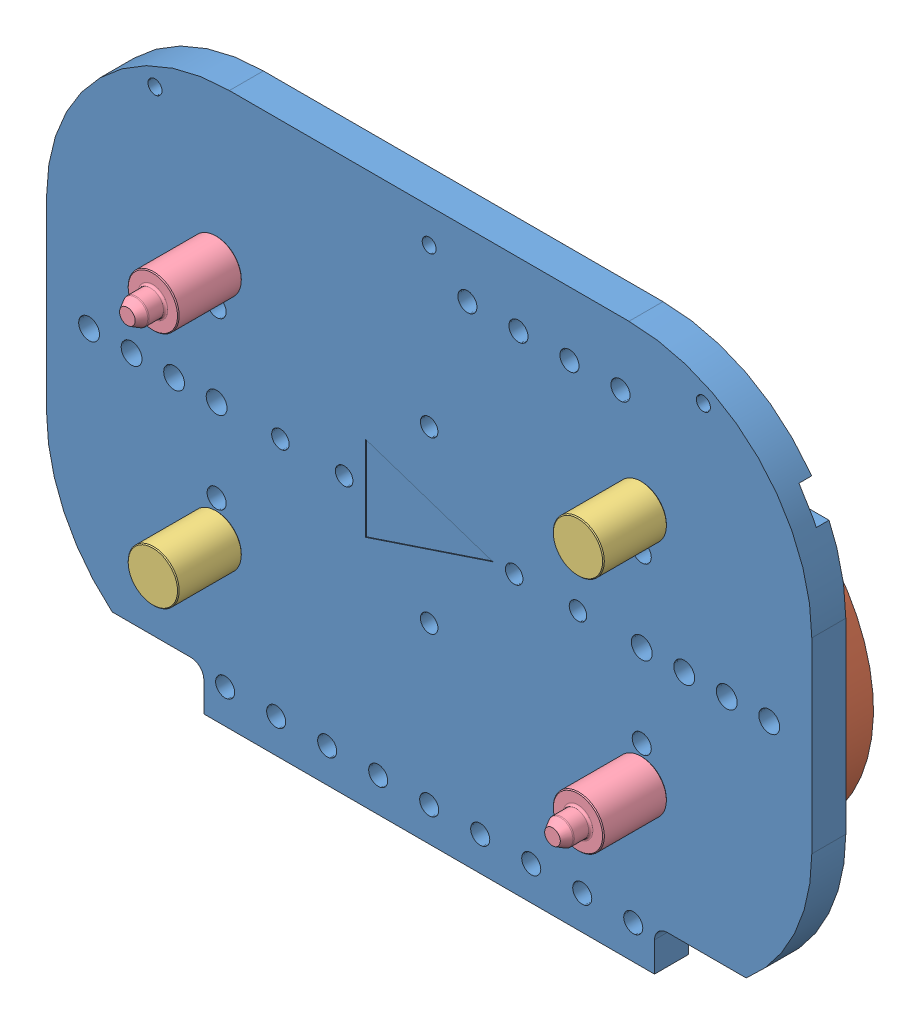
SolidWorks assembly 014-055a_Werkst_X2_00FC_X0_cktr_X2_00E4_X0_ger-80_E-Band-mit Fixierbolzen, configuration Default. Lengths in mm.
Overall size (180 130 36.5).
18 component instances, 8 part files, 0 mates.
Components (placement in the parent):
- 014-119b_Grundtr_X2_00E4_X0_ger-80_E-Band-1: 014-119b_Grundtr_X2_00E4_X0_ger-80_E-Band [Default] at origin size (180 130 8)
- 014-133_Scheibe d80-1: 014-133_Scheibe d80 [Default] at (-50 0 0) x (1 0 0) z (0 0 -1) size (80 80 7.5)
- 014-133_Scheibe d80-2: 014-133_Scheibe d80 [Default] at (50 0 0) x (1 0 0) z (0 0 -1) size (80 80 7.5)
- DIN 915 - M5 x 8-1: DIN 915 - M5 x 8 [Default] at (45 50 0) x (0 0 1) z (-1 0 0) (suppressed, hidden)
- DIN 915 - M5 x 8-2: DIN 915 - M5 x 8 [Default] at (33 50 0) x (0 0 1) z (-1 0 0) (suppressed, hidden)
- DIN 915 - M5 x 8-3: DIN 915 - M5 x 8 [Default] at (21 50 0) x (0 0 1) z (-1 0 0) (suppressed, hidden)
- DIN 915 - M5 x 8-4: DIN 915 - M5 x 8 [Default] at (9 50 0) x (0 0 1) z (-1 0 0) (suppressed, hidden)
- DIN 7991 - M6x12-1: DIN 7991 - M6x12 [Default] at (-50 0 -6.95) x (0 -1 0) z (0 0 -1) (suppressed, hidden)
- DIN 7991 - M6x12-2: DIN 7991 - M6x12 [Default] at (50 0 -6.95) x (0 -1 0) z (0 0 -1) (suppressed, hidden)
- 014-132_Abstandshalter-Auflage-1: 014-132_Abstandshalter-Auflage [Default] at (-50 -28 8) size (12 12 17.8)
- 014-132_Abstandshalter-Auflage-2: 014-132_Abstandshalter-Auflage [Default] at (50 28 8) size (12 12 17.8)
- 014-132_Abstandshalter-Fang-1: 014-132_Abstandshalter-Fang [Default] at (-50 28 8) size (12 12 23.8)
- 014-132_Abstandshalter-Fang-2: 014-132_Abstandshalter-Fang [Default] at (50 -28 8) size (12 12 23.8)
- ISO 7380 - M4 x 10-1: ISO 7380 - M4 x 10 [Default] at (-50 -28 3) x (0 0 1) z (0 1 0) size (12.2 7.6 7.6)
- ISO 7380 - M4 x 10-2: ISO 7380 - M4 x 10 [Default] at (-50 28 3) x (0 0 1) z (0 1 0) size (12.2 7.6 7.6)
- ISO 7380 - M4 x 10-3: ISO 7380 - M4 x 10 [Default] at (50 -28 3) x (0 0 1) z (0.842401 0.538852 0) size (12.2 7.6 7.6)
- ISO 7380 - M4 x 10-4: ISO 7380 - M4 x 10 [Default] at (50 28 3) x (0 0 1) z (0 1 0) size (12.2 7.6 7.6)
- TW-R16-B128_RFID-Datentr_X2_00E4_X0_ger-1: TW-R16-B128_RFID-Datentr_X2_00E4_X0_ger [Default] at (-8 55 1.5) x (1 0 0) z (0 1 0) (suppressed, hidden)
